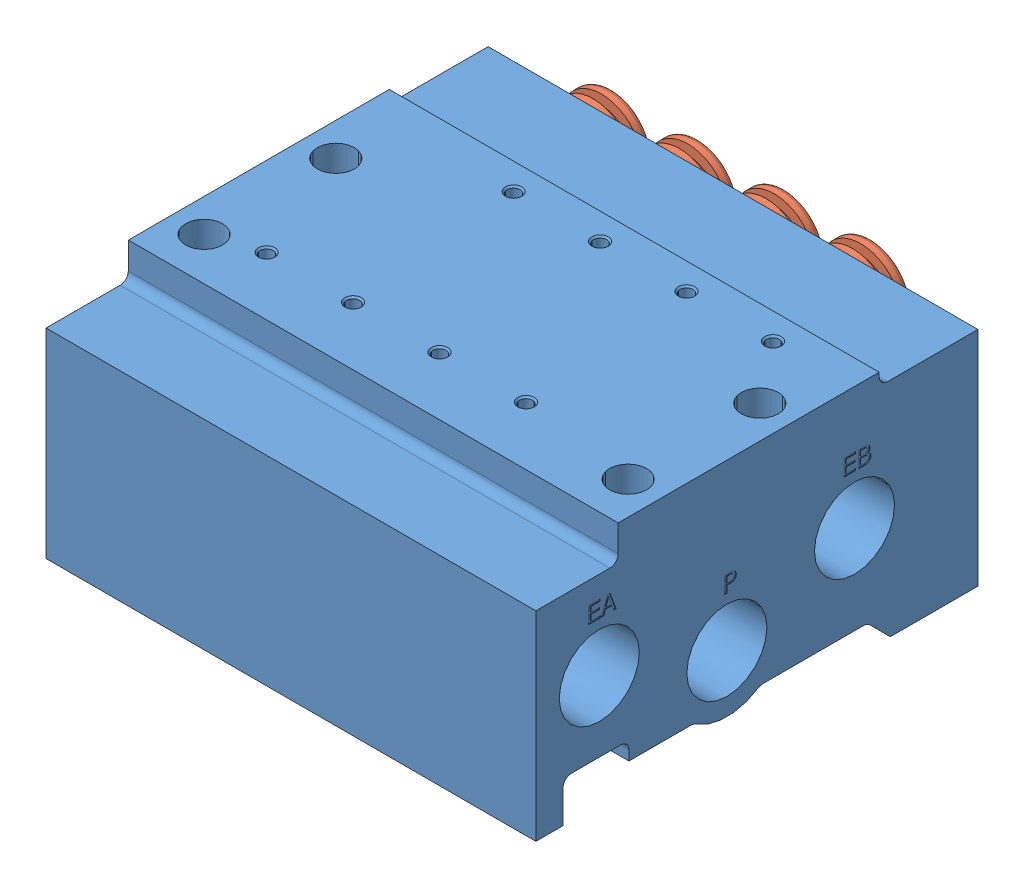
SolidWorks assembly 4 Station Manifold 217-2952, configuration Default. Lengths in mm.
Overall size (59.5 28.5 58.2).
9 component instances, 2 part files, 0 mates.
Components (placement in the parent):
- Copy of 217-2952-001 Rev1_41^4 Station Manifold 217-2952-1: Copy of 217-2952-001 Rev1_41^4 Station Manifold 217-2952 [Default] at origin size (59.5 28.5 53.7) (virtual)
- Copy of 217-2952-002 Rev1_1000-50A-N7^4 Station Manifold 217-2952-1: Copy of 217-2952-002 Rev1_1000-50A-N7^4 Station Manifold 217-2952 [Default] at (-10.5 -22 -15.65) x (1 0 0) z (0 0 -1) size (10 10 15.7) (virtual)
- Copy of 217-2952-002 Rev1_1000-50A-N7^4 Station Manifold 217-2952-2: Copy of 217-2952-002 Rev1_1000-50A-N7^4 Station Manifold 217-2952 [Default] at (-17.5 -7.8 -15.65) x (1 0 0) z (0 0 -1) size (10 10 15.7) (virtual)
- Copy of 217-2952-002 Rev1_1000-50A-N7^4 Station Manifold 217-2952-3: Copy of 217-2952-002 Rev1_1000-50A-N7^4 Station Manifold 217-2952 [Default] at (-21 -22 -15.65) x (1 0 0) z (0 0 -1) size (10 10 15.7) (virtual)
- Copy of 217-2952-002 Rev1_1000-50A-N7^4 Station Manifold 217-2952-4: Copy of 217-2952-002 Rev1_1000-50A-N7^4 Station Manifold 217-2952 [Default] at (-28 -7.8 -15.65) x (1 0 0) z (0 0 -1) size (10 10 15.7) (virtual)
- Copy of 217-2952-002 Rev1_1000-50A-N7^4 Station Manifold 217-2952-5: Copy of 217-2952-002 Rev1_1000-50A-N7^4 Station Manifold 217-2952 [Default] at (-31.5 -22 -15.65) x (1 0 0) z (0 0 -1) size (10 10 15.7) (virtual)
- Copy of 217-2952-002 Rev1_1000-50A-N7^4 Station Manifold 217-2952-6: Copy of 217-2952-002 Rev1_1000-50A-N7^4 Station Manifold 217-2952 [Default] at (-38.5 -7.8 -15.65) x (1 0 0) z (0 0 -1) size (10 10 15.7) (virtual)
- Copy of 217-2952-002 Rev1_1000-50A-N7^4 Station Manifold 217-2952-7: Copy of 217-2952-002 Rev1_1000-50A-N7^4 Station Manifold 217-2952 [Default] at (-42 -22 -15.65) x (1 0 0) z (0 0 -1) size (10 10 15.7) (virtual)
- Copy of 217-2952-002 Rev1_1000-50A-N7^4 Station Manifold 217-2952-8: Copy of 217-2952-002 Rev1_1000-50A-N7^4 Station Manifold 217-2952 [Default] at (-49 -7.8 -15.65) x (1 0 0) z (0 0 -1) size (10 10 15.7) (virtual)
